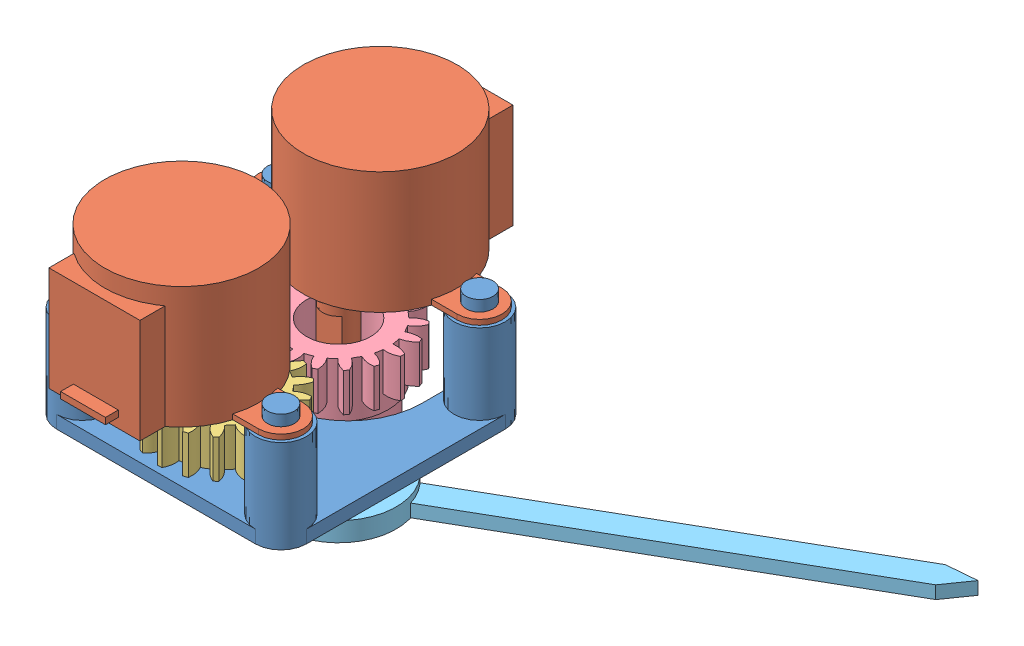
SolidWorks assembly clock_subassem, configuration Default. Lengths in mm.
Overall size (87.32 49 84.33).
6 component instances, 5 part files, 14 mates.
Components (placement in the parent):
- clock_frame-1: clock_frame [Default] at (12.461 15.2659 30.0819) size (39 17 39)
- clock_stepper_28byj-48-1: clock_stepper_28byj-48 [Default] at (12.461 46.7659 45.5819) x (-1 0 0) z (0 -1 0) size (38 27.6 29)
- clock_stepper_28byj-48-2: clock_stepper_28byj-48 [Default] at (12.461 46.7659 14.5819) x (1 0 0) z (0 -1 0) size (38 27.6 29)
- clock_gear_stepper-1: clock_gear_stepper [Default] at (25.2839 -5.1828 38.8346) x (0 -1 0) z (-0.986 0 -0.166746) size (8 19.8 20)
- clock_gear_hour-1: clock_gear_hour [Default] at (12.7819 36.136 30.0221) x (0 1 0) z (-0.498534 0 -0.86687) size (24 19.8 20)
- clock_hand_hour-1: clock_hand_hour [Default] at (12.461 -2.2341 21.0819) x (0.498534 0 0.86687) z (0 1 0) size (18 82.06 3)
Mates (geometry in assembly coordinates):
- Concentric1: concentric anti-aligned: circle of clock_frame-1; circle of clock_stepper_28byj-48-1
- Concentric2: concentric aligned: circle of clock_frame-1; circle of clock_stepper_28byj-48-1
- Coincident3: coincident anti-aligned: plane of clock_frame-1 through (12.461 27.7659 30.0819) normal (0 1 0); plane of clock_stepper_28byj-48-1 through (12.461 27.7659 45.5819) normal (0 -1 0)
- Coincident4: coincident aligned: circle of clock_frame-1; plane of clock_stepper_28byj-48-2 through (12.461 27.7659 14.5819) normal (0 -1 0)
- Concentric3: concentric aligned: circle of clock_frame-1; circle of clock_stepper_28byj-48-2
- Concentric4: concentric anti-aligned: circle of clock_frame-1; circle of clock_stepper_28byj-48-2
- Coincident7: coincident anti-aligned: plane of clock_stepper_28byj-48-1 through (12.461 23.7659 45.5819) normal (0 -1 0); plane of clock_gear_stepper-1 through (12.461 23.7659 39.0819) normal (0 1 0)
- Concentric5: concentric anti-aligned: circle of clock_stepper_28byj-48-1; circle of clock_gear_stepper-1
- Concentric6: concentric aligned: circle of clock_stepper_28byj-48-2; circle of clock_gear_hour-1
- Coincident8: coincident aligned: plane of clock_frame-1 through (12.461 13.2659 30.0819) normal (0 -1 0); plane of clock_gear_hour-1 through (12.7819 13.2659 30.0221) normal (0 -1 0)
- Concentric7: concentric aligned: circle of clock_gear_hour-1; circle of clock_hand_hour-1
- Coincident9: coincident aligned: plane of clock_gear_hour-1 through (12.461 -2.2341 21.0819) normal (0 -1 0); plane of clock_hand_hour-1 through (12.461 -2.2341 21.0819) normal (0 -1 0)
- Coincident10: coincident: point of clock_gear_hour-1; line of clock_hand_hour-1 through (10.3526 -2.2341 14.4069) axis (0.498534 0 0.86687)
- GearMate2: gear = 15.498 : 15.498 mm: cylinder of clock_gear_stepper-1 through (12.461 15.7659 39.0819) axis (0 1 0) radius 7.749; cylinder of clock_gear_hour-1 through (12.461 21.7659 21.0819) axis (0 -1 0) radius 7.749
